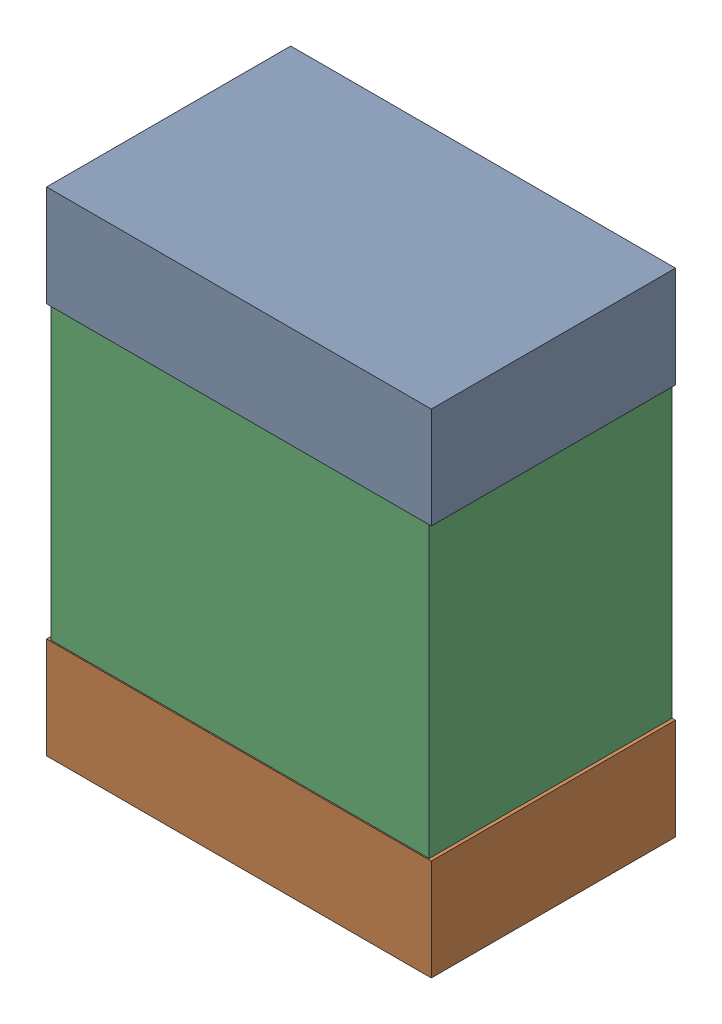
SolidWorks assembly CinB1Kanaloa_v2.0.0_Power, configuration Default. Lengths in mm.
Overall size (2.85 3.65 1.81).
6 component instances, 2 part files, 0 mates.
Components (placement in the parent):
- 334789552-1: 334789552 [Default] at (51.2 81.925 0) size (2.85 0.75 1.81)
  - Extruded_9-1: Extruded_9 [Default] at origin size (2.85 0.75 1.81)
- 334789552-2: 334789552 [Default] at (51.2 79.025 0) size (2.85 0.75 1.81)
  - Extruded_9-1: Extruded_9 [Default] at origin size (2.85 0.75 1.81)
- 334789424-1: 334789424 [Default] at (51.2 80.475 0) size (2.8 3.6 1.8)
  - Extruded_10-1: Extruded_10 [Default] at origin size (2.8 3.6 1.8)
